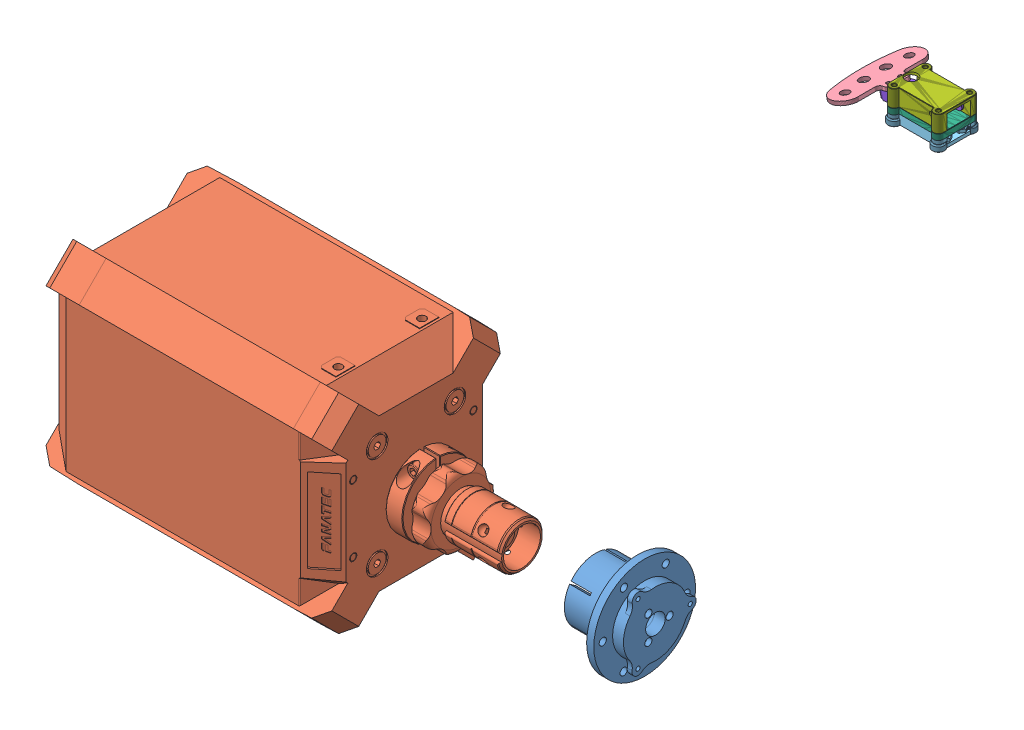
SolidWorks assembly arduino fanatec wheel, configuration Default. Lengths in mm.
Overall size (515.09 298.9 404.58).
9 component instances, 8 part files, 7 mates.
Components (placement in the parent):
- fanatec adapter-1: fanatec adapter [Default] at (307.0006 0 80) x (0 0.999995 -0.003311) z (1 0 0) size (85 85 50)
- Fanatec_PodiumWB-DD1-DD2-1: Fanatec_PodiumWB-DD1-DD2 [Default] at origin size (403.59 175 155)
- fanatec SPI connector-1: fanatec SPI connector [Default] at (293.0006 0 80) x (0 0.999995 -0.003311) z (1 0 0) size (30 30.35 17)
- mangentic pedal shifters assy-2: mangentic pedal shifters assy [Default] at (238.0891 184.3999 -229.3557) size (83.11 27 75.95)
  - f1_paddle-1: f1_paddle [Default] at (-2.6636 15.9027 55.725) x (-0.975758 -0.218853 0) z (0 0 -1) size (33.6 3 75.95)
  - shifter_unit_btm-1: shifter_unit_btm [Default] at origin size (47 8 36)
  - shifter_unit_switch_stop_plate-1: shifter_unit_switch_stop_plate [Default] at (-7 8 35) x (1 0 0) z (0 1 0) size (53 34 5)
  - shifter_unit_top-1: shifter_unit_top [Default] at (0.9034 13 35) x (1 0 0) z (0 1 0) size (45 34 14)
  - paddle_hinge_v2-2: paddle_hinge_v2 [Default] at (-10.1177 3.2187 27.5) x (0.975758 0.218853 0) z (-0.218853 0.975758 0) size (52 19.5 10.74)
Mates (geometry in assembly coordinates):
- Coincident1: coordinate: point of Fanatec_PodiumWB-DD1-DD2-1
- Concentric1: concentric anti-aligned: cylinder of fanatec adapter-1 through (272.0006 0 80) axis (1 0 0) radius 19.15; cylinder of Fanatec_PodiumWB-DD1-DD2-1 through (208.1118 0 80) axis (-1 0 0) radius 19
- Coincident3: coincident anti-aligned: line of fanatec adapter-1 through (272.0006 2.9555 96.7411) axis (1 0 0); line of Fanatec_PodiumWB-DD1-DD2-1 through (210.5 2.9555 96.7411) axis (-1 0 0)
- Coincident4: coincident anti-aligned: plane of fanatec adapter-1 through (307.0006 0 80) normal (-1 0 0); plane of Fanatec_PodiumWB-DD1-DD2-1 through (210.5 -17.3434 97) normal (1 0 0)
- Coincident6: coincident anti-aligned: plane of fanatec adapter-1 through (307.0006 0 80) normal (-1 0 0); plane of fanatec SPI connector-1 through (307.0006 0 80) normal (1 0 0)
- Concentric3: concentric anti-aligned: cylinder of fanatec adapter-1 through (272.0006 0 80) axis (1 0 0) radius 19.15; cylinder of fanatec SPI connector-1 through (290.0006 0 80) axis (-1 0 0) radius 9.7
- Coincident7: coincident aligned: plane of fanatec adapter-1 through (307.0006 0 80) normal (0 0.999995 -0.003311); plane of fanatec SPI connector-1 through (293.0006 0 80) normal (0 0.999995 -0.003311)
